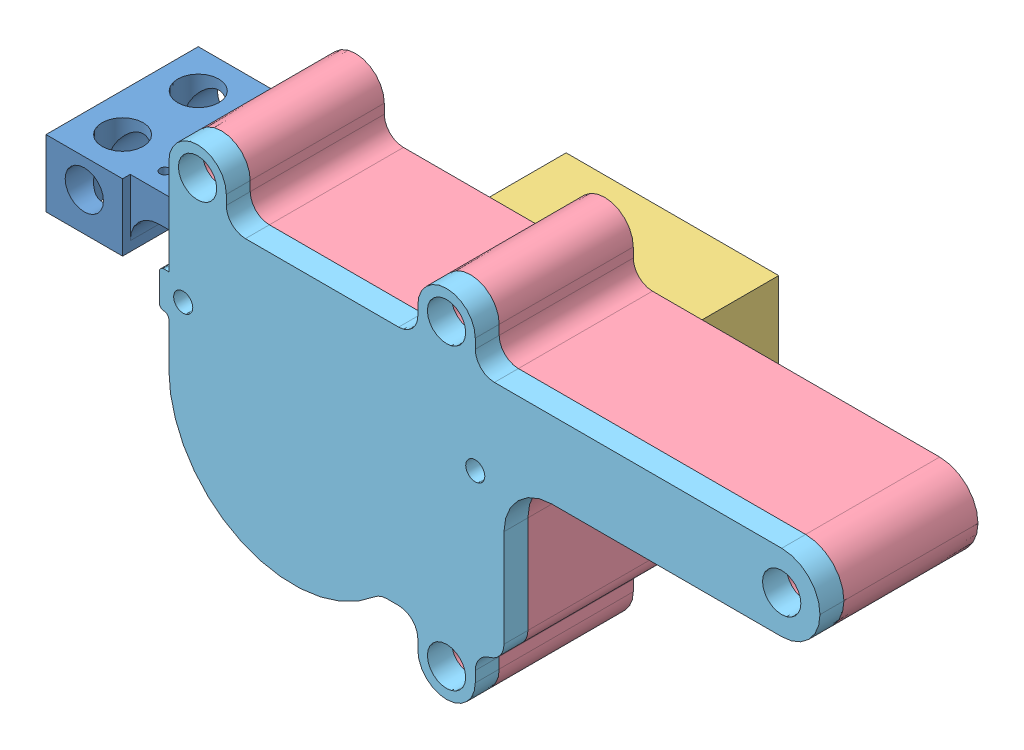
SolidWorks assembly Proton_Rev2, configuration Standard. Lengths in mm.
Overall size (80.83 37.18 34.6).
7 component instances, 6 part files, 22 mates.
Components (placement in the parent):
- rack gear-1: rack gear [Standard] at (25.6971 60.6031 -1.6754) x (1 0 0) z (0 -1 0) size (70 15.9 7)
  - rack gear body-1: rack gear body [Standard] at (-48.626 8.3754 -1.5) size (70 15.9 7)
  - rack spur-3: rack spur [ISO - Rack-spur - rectangular 1M 20PA 3.4FW 4.7PH 54.3L---SAll] at (-73.826 6.4754 -3) x (1 0 0) z (0 -1 0) size (54.3 5.7 3.4)
- TowerServoSG92R-2: TowerServoSG92R [Standard] at (-27.1117 48.5083 -6.05) x (-1 0 0) z (0 0 1) size (32.2 12 29.65)
- P-Body-1: P-Body [Standard] at (-45.1019 64.6031 -5) size (69 37.18 14)
- Cover-1: Cover [Standard] at (-10.2437 64.6031 11.5) x (1 0 0) z (0 0 -1) size (69 37.18 3.1)
- helical gear-7: helical gear [ISO - RH Helical gear 1M 20T 10HA 20PA 4FW ---20A75H50L6.0N] at (-32.2367 48.5083 3.55) x (0 0 1) z (0.919548 0.392978 0) size (4 22.31 22.31)
Mates (geometry in assembly coordinates):
- Parallel1: parallel aligned: plane of TowerServoSG92R-2 through (-11.0117 42.5083 -5) normal (0 -1 0); plane of P-Body-1 through (14.8981 56.6031 9) normal (0 -1 0)
- Deckungsgleich22: coincident anti-aligned: plane of TowerServoSG92R-2 through (-27.1117 48.5083 -5) normal (0 0 1); plane of P-Body-1 through (-32.1019 48.8031 -5) normal (0 0 -1)
- Deckungsgleich28: coincident aligned: plane of P-Body-1 through (-45.1019 64.6031 9) normal (0 1 0); plane of Cover-1 through (14.8981 64.6031 9) normal (0 1 0)
- Deckungsgleich29: coincident aligned: plane of P-Body-1 through (-45.1019 64.6031 9) normal (-1 0 0); plane of Cover-1 through (-45.1019 64.6031 9) normal (-1 0 0)
- Deckungsgleich30: coincident anti-aligned: plane of P-Body-1 through (-32.1019 48.8031 9) normal (0 0 1); plane of Cover-1 through (-32.1019 48.8031 9) normal (0 0 -1)
- Deckungsgleich31: coincident aligned: plane of rack gear-1/rack gear body-1 through (-57.9289 57.6031 11.5) normal (0 0 1); plane of Cover-1 through (-32.1019 48.8031 11.5) normal (0 0 1)
- Zahnstange/Ritzel-Verknüpfung1: rack pinion = 22.1746 mm: line of rack gear-1/rack gear body-1 through (-3.9808 60.6031 10.7) axis (-1 0 0); circle of ?
- Deckungsgleich32: coincident anti-aligned: plane of rack gear-1/rack gear body-1 through (-22.9289 63.6031 6.7) normal (0 1 0); plane of P-Body-1 through (-45.1019 63.6031 2.1) normal (0 -1 0)
- Deckungsgleich34: coincident anti-aligned: plane of ? through (-32.2783 48.5083 3.55) normal (0 0 -1); plane of TowerServoSG92R-2 through (-27.1533 48.5083 3.55) normal (0 0 1)
- Konzentrisch1: concentric anti-aligned: cylinder of ? through (-32.2783 48.5083 3.55) axis (0 0 1) radius 2.4; cylinder of TowerServoSG92R-2 through (-32.2783 48.5083 6.55) axis (0 0 -1) radius 2
- Konzentrisch2: concentric aligned: cylinder of TowerServoSG92R-2 through (-13.4992 48.5083 -15) axis (0 0 1) radius 1.05; cylinder of P-Body-1 through (-13.4992 48.5083 -5) axis (0 0 1) radius 1
- Konzentrisch3: concentric anti-aligned: cylinder of TowerServoSG92R-2 through (-32.2367 48.5083 6.55) axis (0 0 -1) radius 2; cylinder of ? through (-32.2367 48.5083 -54.95) axis (0 0 1) radius 3
- Deckungsgleich35: coincident anti-aligned: plane of TowerServoSG92R-2 through (-27.1117 48.5083 3.55) normal (0 0 1); plane of ? through (-32.2367 48.5083 3.55) normal (0 0 -1)
- Zahnstange/Ritzel-Verknüpfung2: rack pinion = 22.3085 mm: line of ? through (-33.9945 60.1531 8.2) axis (1 0 0); cylinder of ? through (-32.2367 48.5083 17.55) axis (0 0 1) radius 11.1543
- Konzentrisch4: concentric anti-aligned: cylinder of TowerServoSG92R-2 through (-32.2367 48.5083 6.55) axis (0 0 -1) radius 2; cylinder of ? through (-32.2367 48.5083 -54.95) axis (0 0 1) radius 3
- Deckungsgleich36: coincident anti-aligned: plane of TowerServoSG92R-2 through (-27.1117 48.5083 3.55) normal (0 0 1); plane of ? through (-32.2367 48.5083 3.55) normal (0 0 -1)
- Konzentrisch5: concentric anti-aligned: cylinder of TowerServoSG92R-2 through (-32.2367 48.5083 6.55) axis (0 0 -1) radius 2; cylinder of ? through (-32.2367 48.5083 -54.95) axis (0 0 1) radius 3
- Deckungsgleich37: coincident: plane of TowerServoSG92R-2 through (-27.1117 48.5083 3.55) normal (0 0 1); plane of ? through (-32.2367 48.5083 3.55) normal (0 0 -1)
- Konzentrisch6: concentric aligned: cylinder of TowerServoSG92R-2 through (-32.2367 48.5083 6.55) axis (0 0 -1) radius 2; cylinder of ? through (-32.2367 48.5083 7.55) axis (0 0 -1) radius 4.15
- Deckungsgleich38: coincident anti-aligned: plane of TowerServoSG92R-2 through (-27.1117 48.5083 3.55) normal (0 0 1); plane of helical gear-7 through (-32.2367 48.5083 3.55) normal (0 0 -1)
- Konzentrisch7: concentric anti-aligned: cylinder of TowerServoSG92R-2 through (-32.2367 48.5083 6.55) axis (0 0 -1) radius 2; cylinder of helical gear-7 through (-32.2367 48.5083 3.55) axis (0 0 1) radius 4.15
- Zahnstange/Ritzel-Verknüpfung3: rack pinion = 22.3085 mm: line of rack gear-1/rack spur-3 through (-36.8259 57.9031 8.2) axis (-1 0 0); circle of helical gear-7
